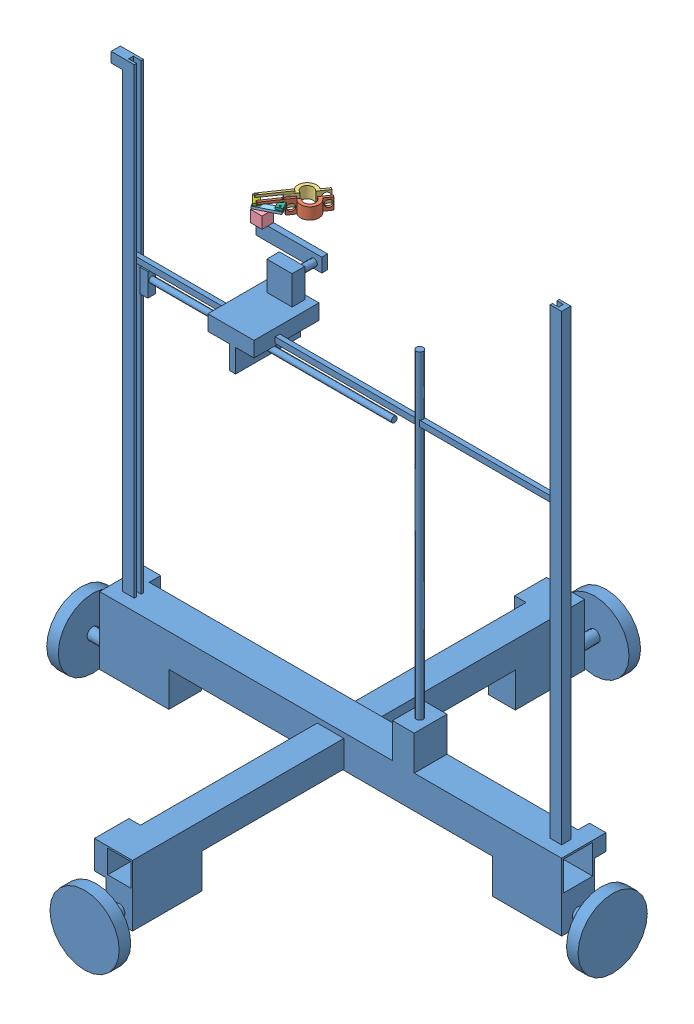
SolidWorks assembly atomatic full, configuration Default. Lengths in mm.
Overall size (460 478.4 451.4).
8 component instances, 7 part files, 3 mates.
Components (placement in the parent):
- aotomatic-1: aotomatic [Default] at (18.4048 102.9443 325.4756) size (460 478.4 451.4)
- clamp asse-1: clamp asse [Default] at (90.9198 378.6142 293.8575) x (-0.230927 0.056393 -0.971335) z (0.97276 0.034176 -0.229282) size (52.05 17.12 53.17)
  - clamp1-1: clamp1 [Default] at (39.7099 20.3856 29.9122) x (-0.667727 0.063142 -0.741723) z (0.742267 -0.019008 -0.669835) size (48 12 10)
  - clamp2-1: clamp2 [Default] at (47.1595 20.1851 23.4741) x (0.667727 -0.063142 0.741723) z (-0.742267 0.019008 0.669835) size (48 12 10.06)
  - servo-1: servo [Default] at (19.7116 18.0314 4.2152) x (0.971335 -0.062749 0.229282) z (-0.230927 -0.020266 0.97276) size (10 10 10)
  - servo face-1: servo face [Default] at (19.5138 28.1611 1.3899) x (0.228542 -0.046223 0.972436) z (-0.971899 0.047028 0.230652) size (20 4 5)
  - link1-2: link1 [Default] at (29.131 29.073 17.4173) x (-0.975231 0.047719 0.21598) z (-0.213879 0.045509 -0.975799) size (10 2 5)
  - link2-3: link2 [Default] at (25.1444 29.8444 1.4736) x (-0.843213 0.02927 0.536783) z (-0.534614 0.059089 -0.843028) size (10 2 5)
Mates (geometry in assembly coordinates):
- Coincident1: coincident anti-aligned: plane of aotomatic-1 through (144.6714 397.862 268.5386) normal (0 1 0); plane of clamp asse-1/servo-1 through (90.1029 397.862 274.876) normal (0 -1 0)
- Coincident3: coincident aligned: plane of aotomatic-1 through (18.4048 102.9443 268.5386) normal (0 0 -1); plane of clamp asse-1/servo-1 through (87.909 407.862 268.5386) normal (0 0 -1)
- Lock3: lock: unknown of aotomatic-1; unknown of clamp asse-1/servo-1
